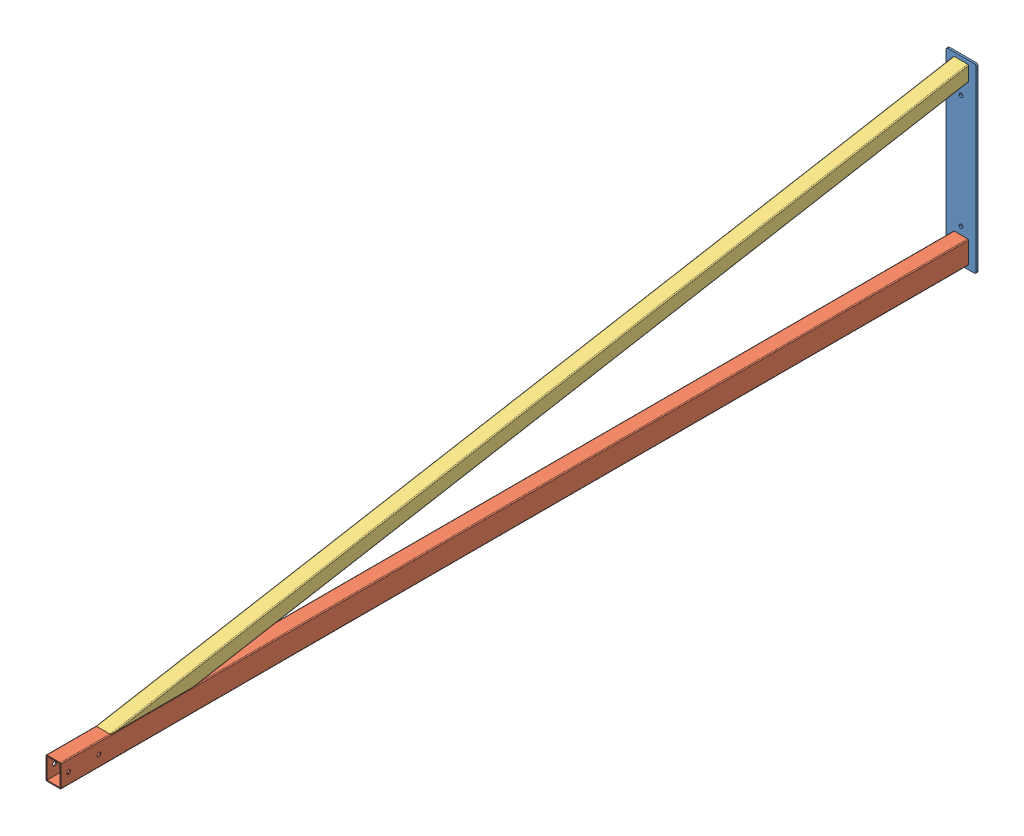
SolidWorks assembly curtain arm assy, configuration Default. Lengths in mm.
Overall size (101.6 609.6 3056.82).
3 component instances, 3 part files, 6 mates.
Components (placement in the parent):
- tube mount-1: tube mount [Default] at origin size (101.6 609.6 6.35)
- curtain arm main-1: curtain arm main [Default] at (0 -254 1530.35) size (50.8 76.2 3048)
- gusset tube-1: gusset tube [Default] at (0 2.4461 1502.7864) x (1 0 0) z (0 -0.173648 0.984808) size (50.8 50.8 2925.46)
Mates (geometry in assembly coordinates):
- Coincident1: coincident anti-aligned: plane of tube mount-1 through (-44.45 298.45 6.35) normal (0 0 1); plane of curtain arm main-1 through (-22.225 -288.925 6.35) normal (0 0 -1)
- Coincident2: coincident aligned: plane of curtain arm main-1 through (0 -254 1530.35) normal (1 0 0); plane of assembly through (0 0 0) normal (1 0 0)
- Coincident3: coincident aligned: plane of gusset tube-1; plane of assembly through (0 0 0) normal (1 0 0)
- Distance1: distance = 12.7 mm aligned: plane of curtain arm main-1 through (-22.225 -292.1 3054.35) normal (0 -1 0); plane of tube mount-1 through (-44.45 -304.8 6.35) normal (0 -1 0)
- Coincident5: coincident anti-aligned: plane of tube mount-1 through (-44.45 298.45 6.35) normal (0 0 1); plane of gusset tube-1 through (-25.4 292.1 6.35) normal (0 0 -1)
- Distance2: distance = 12.7 mm: line of gusset tube-1 through (22.225 292.1 6.35) axis (-1 0 0); plane of tube mount-1 through (-44.45 304.8 6.35) normal (0 1 0)
